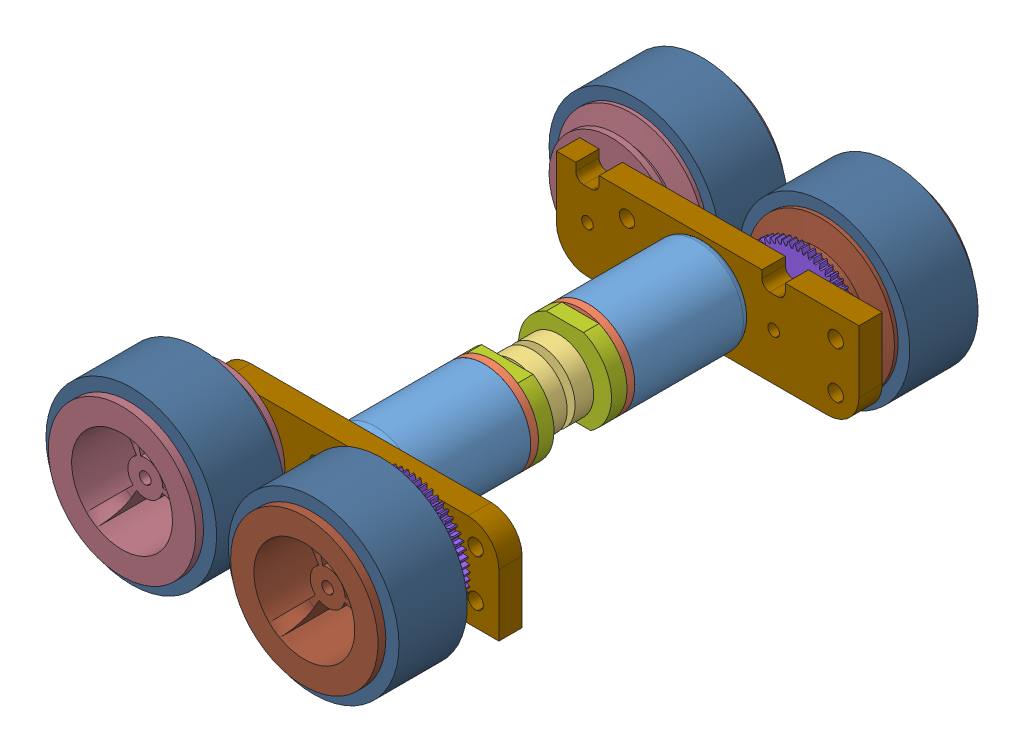
SolidWorks assembly Mouse, configuration Default. Lengths in mm.
Overall size (50.17 28.44 77.05).
32 component instances, 13 part files, 3 mates.
Components (placement in the parent):
- Drive System-1: Drive System [Default] at (24.1107 25.7131 41.5885) size (48.41 26.54 38.28)
  - Motor-1: Motor [Default] at (-3.0003 1.1346 8.6863) size (14.57 14.57 26.2)
    - body-1: body [Default] at (7.0099 12.5359 7.5707) size (12 12 15)
    - back cover-1: back cover [Default] at (7.0099 12.5359 6.5707) x (0.969512 0.245046 0) z (0 0 1) size (12 12 1)
    - magnet-1: magnet [Default] at (7.0099 12.5359 1.3707) x (0.345341 -0.938477 0) z (0 0 1) size (9 9 2.4)
    - spur gear_am-1: spur gear_am [Metric - Spur gear 0.25M 10T 20PA 3FW ---S10N75H50L1N] at (7.0099 12.5359 24.5707) x (0 0 1) z (-0.822446 0.568843 0) size (3 2.87 3)
    - rod-1: rod [Default] at (7.0099 12.5359 1.3707) x (0.869463 0.493997 0) z (0 0 1) size (1 1 26.2)
    - brass bearing-1: brass bearing [Default] at (7.0099 12.5359 22.5707) x (0.921198 0.389094 0) z (0 0 1) size (3.5 3.5 1)
    - PCB-1: PCB [Default] at (7.0099 12.5359 4.5707) size (12 10.5 2)
  - Wheel gear 61T-1: Wheel gear 61T [Metric - Spur gear 0.25M 61T 20PA 1mmFW ---S61N75H50L1.5N] at (12.9096 13.6705 35.8373) x (0 0 -1) z (0.358677 0.933462 0) size (1 15.74 15.75)
  - holder-1: holder [Default] at (8.0096 13.6705 31.257) size (39 12 3)
  - Tyre-1: Tyre [Default] at (-11.0904 13.6705 37.8373) x (0.972185 -0.234215 0) z (0 0 1) size (22 22 8.8)
  - Tyre-2: Tyre [Default] at (12.9096 13.6705 38.3373) x (0.012858 -0.999917 0) z (0 0 1) size (22 22 8.8)
  - Rim-2: Rim [Default] at (12.9096 13.6705 38.3373) x (0.999939 0.011006 0) z (0 0 1) size (19 19 12.5)
  - wheel_subgear-1: wheel_subgear [Metric - Spur gear 0.3M 12T 20PA 1.7FW ---S12N75H50L1.5N] at (12.9096 13.6705 35.8373) x (0 0 1) z (-0.735235 0.677812 0) size (1.7 4.08 4.08)
  - Rim_nogear-1: Rim_nogear [Default] at (-11.0904 13.6705 37.8373) size (19 19 13)
- Drive System-5: Drive System [Default] at (24.1107 53.054 60.6854) x (1 0 0) z (0 0 -1) size (50.17 28.44 37.78) (flexible)
  - Motor-1: Motor [Default] at (-3.0003 1.1346 8.6863) size (14.57 14.57 26.2)
    - body-1: body [Default] at (7.0099 12.5359 7.5707) size (12 12 15)
    - back cover-1: back cover [Default] at (7.0099 12.5359 6.5707) x (0.969512 0.245046 0) z (0 0 1) size (12 12 1)
    - magnet-1: magnet [Default] at (7.0099 12.5359 1.3707) x (0.345341 -0.938477 0) z (0 0 1) size (9 9 2.4)
    - spur gear_am-1: spur gear_am [Metric - Spur gear 0.25M 10T 20PA 3FW ---S10N75H50L1N] at (7.0099 12.5359 24.5707) x (0 0 1) z (-0.822446 0.568843 0) size (3 2.87 3)
    - rod-1: rod [Default] at (7.0099 12.5359 1.3707) x (0.869463 0.493997 0) z (0 0 1) size (1 1 26.2)
    - brass bearing-1: brass bearing [Default] at (7.0099 12.5359 22.5707) x (0.921198 0.389094 0) z (0 0 1) size (3.5 3.5 1)
    - PCB-1: PCB [Default] at (7.0099 12.5359 4.5707) size (12 10.5 2)
  - Wheel gear 61T-1: Wheel gear 61T [Metric - Spur gear 0.25M 61T 20PA 1mmFW ---S61N75H50L1.5N] at (12.9096 13.6705 35.3059) x (0 0 -1) z (0.933109 0.359592 0) size (1 15.74 15.75)
  - holder-1: holder [Default] at (8.0096 13.6705 31.257) size (39 12 3)
  - Tyre-1: Tyre [Default] at (-11.0904 13.6705 37.3059) x (0.933011 0.359847 0) z (0 0 1) size (22 22 8.8)
  - Tyre-2: Tyre [Default] at (12.9096 13.6705 37.8059) x (0.99589 0.090572 0) z (0 0 1) size (22 22 8.8)
  - Rim-2: Rim [Default] at (12.9096 13.6705 37.8059) x (0.999939 0.011006 0) z (0 0 1) size (19 19 12.5)
  - wheel_subgear-1: wheel_subgear [Metric - Spur gear 0.3M 12T 20PA 1.7FW ---S12N75H50L1.5N] at (12.9096 13.6705 35.3059) x (0 0 1) z (-0.735235 0.677812 0) size (1.7 4.08 4.08)
  - Rim_nogear-1: Rim_nogear [Default] at (-11.0904 13.6705 37.3059) size (19 19 13)
Mates (geometry in assembly coordinates):
- Parallel2: parallel: plane of Drive System-1/holder-1 through (13.0203 41.3835 75.8455) normal (0 0 1); plane of Drive System-5/holder-1 through (13.0203 37.3835 26.4283) normal (0 0 -1)
- Coincident2: coincident aligned: plane of Drive System-1/holder-1 through (32.1203 33.3835 75.8455) normal (0 -1 0); plane of Drive System-5/holder-1 through (32.1203 33.3835 26.4283) normal (0 -1 0)
- Coincident3: coincident aligned: plane of Drive System-1/holder-1 through (9.0203 39.3835 75.8455) normal (-1 0 0); plane of Drive System-5/holder-1 through (9.0203 39.3835 26.4283) normal (-1 0 0)
